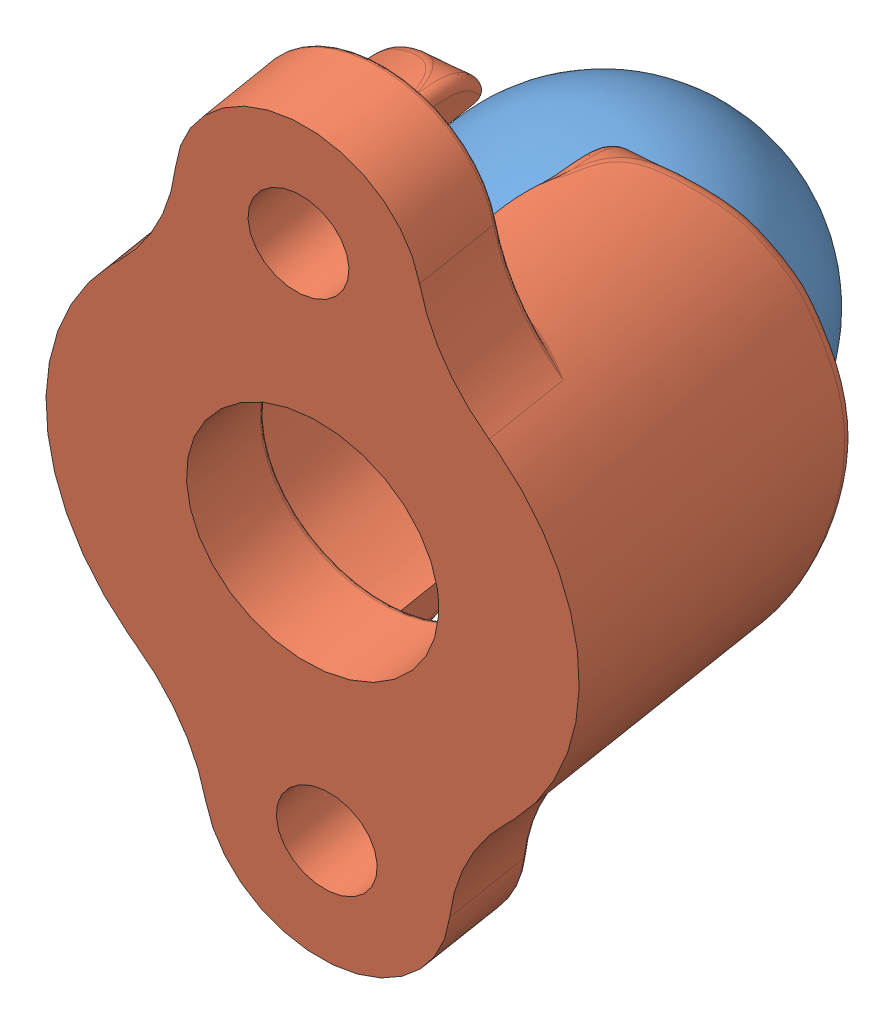
SolidWorks assembly ball_v2, configuration Default. Lengths in mm.
Overall size (19.98 29.54 22.65).
2 component instances, 2 part files, 1 mates.
Components (placement in the parent):
- ball-1: ball [Predeterminado] at (1.5642 3.9174 -7.4116) x (0.97009 -0.147809 -0.192554) z (0.182549 -0.078633 0.980047) size (12.6 12.6 12.6)
- bas-1: bas [Predeterminado] at (3.6231 4.1003 3.995) x (-0.016649 -0.997488 -0.068845) z (0.994727 -0.009555 -0.102116) size (28.57 12.2 18.37)
Mates (geometry in assembly coordinates):
- Tangent1: tangent anti-aligned: sphere of ball-1; face of bas-1
